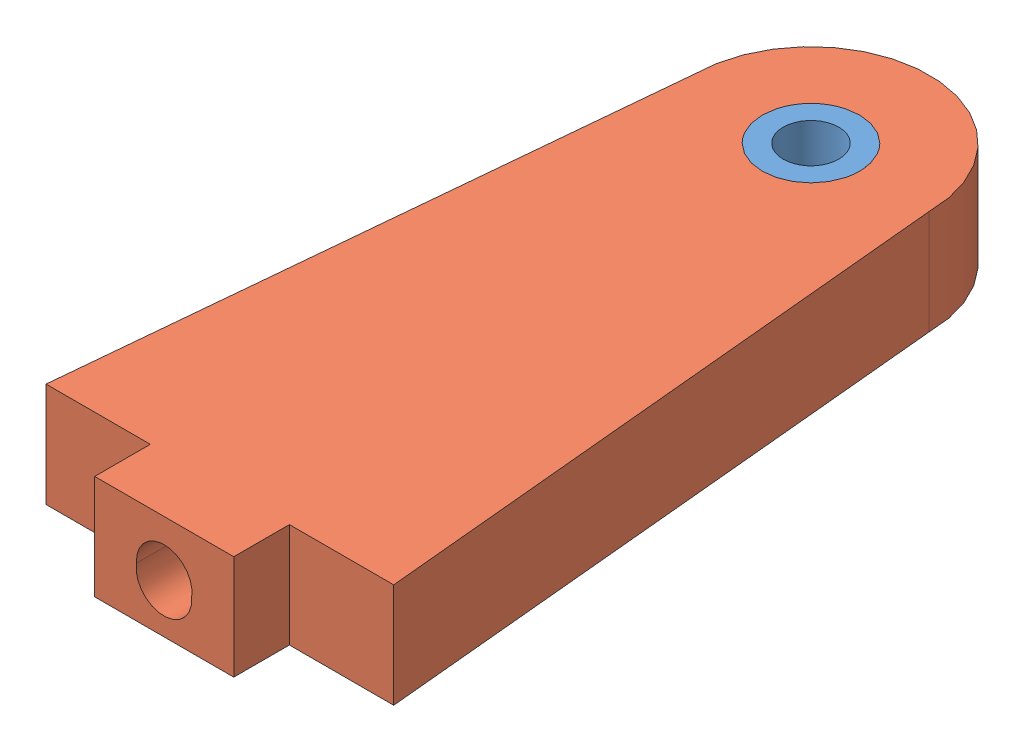
SolidWorks assembly ENDBEARING, configuration Default. Lengths in mm.
Overall size (50 15 110).
2 component instances, 2 part files, 2 mates.
Components (placement in the parent):
- bush-1: bush [Default] at (21.1555 6.0388 -0.5751) size (14 15 14)
- endbearing-1: endbearing [Default] at (21.1555 6.0388 92.4249) x (1 0 0) z (0 1 0) size (50 110 15)
Mates (geometry in assembly coordinates):
- Concentric1: concentric: cylinder of bush-1 through (21.1555 21.0388 -0.5751) axis (0 -1 0) radius 4; cylinder of endbearing-1 through (21.1555 6.0388 -0.5751) axis (0 1 0) radius 7
- Coincident1: coincident aligned: plane of bush-1 through (21.1555 6.0388 -0.5751) normal (0 -1 0); plane of endbearing-1 through (21.1555 6.0388 -0.5751) normal (0 -1 0)
